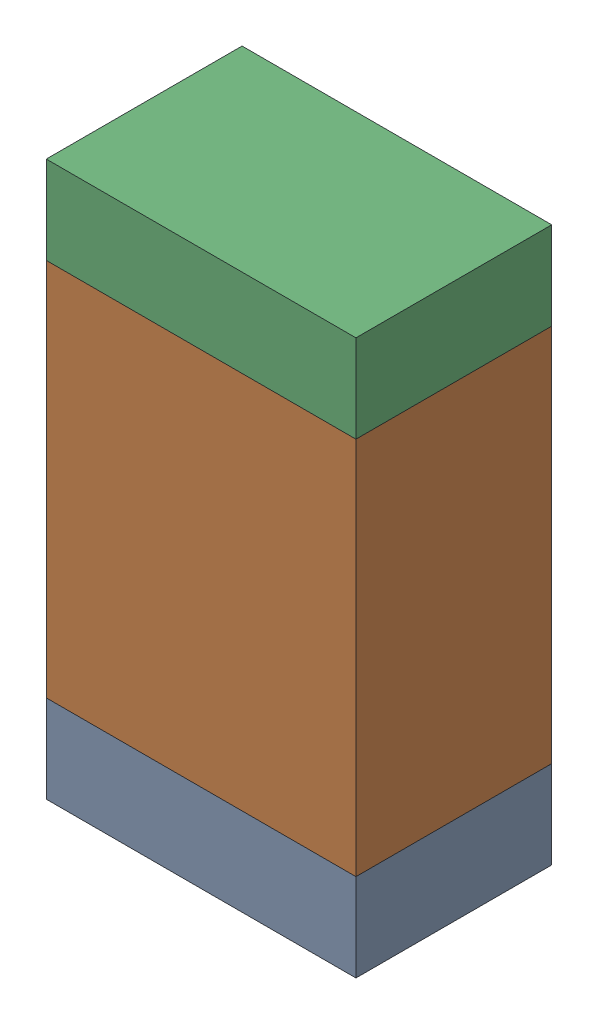
SolidWorks assembly R1, configuration Default. Lengths in mm.
Overall size (0.95 1.7 0.6).
6 component instances, 2 part files, 0 mates.
Components (placement in the parent):
- 959206216-1: 959206216 [Default] at (142.6211 77.6287 0) size (0.95 0.27 0.6)
  - Extruded-1: Extruded [Default] at origin size (0.95 0.27 0.6)
- 959206352-1: 959206352 [Default] at (142.6211 78.3437 0) size (0.95 1.16 0.6)
  - Extruded-1-1: Extruded-1 [Default] at origin size (0.95 1.16 0.6)
- 959206216-2: 959206216 [Default] at (142.6211 79.0587 0) size (0.95 0.27 0.6)
  - Extruded-1: Extruded [Default] at origin size (0.95 0.27 0.6)
